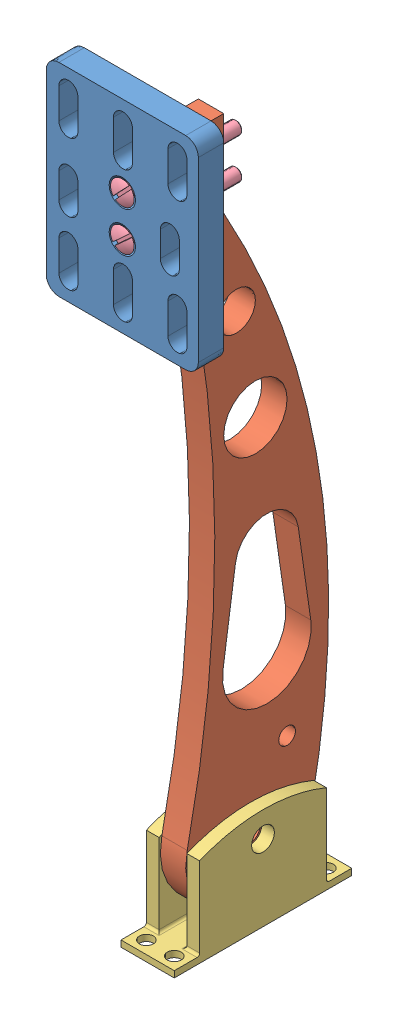
SolidWorks assembly Assem4, configuration Default. Lengths in mm.
Overall size (60 300 82.63).
5 component instances, 4 part files, 9 mates.
Components (placement in the parent):
- Accellerator Pedal-1: Accellerator Pedal [Default] at (-107.6215 -14.9156 18.9179) size (60 80 10)
- Pedal support-1: Pedal support [Default] at (-72.6377 -204.9156 -16.0821) x (-1 0 0) z (0 0 -1) size (10 275 71.45)
- Base Pedal Interface-1: Base Pedal Interface [Default] at (-88.3912 -234.9156 -41.0821) size (21 40 70)
- din_en_iso2010_m5x45_4_8-1: din_en_iso2010_m5x45_4_8 [Default] at (-77.6215 33.0844 30.1179) x (-0.68633 -0.72729 0) z (0 0 -1) size (9.22 9.3 46.18)
- din_en_iso2010_m5x45_4_8-2: din_en_iso2010_m5x45_4_8 [Default] at (-77.6215 17.0844 30.1179) x (-0.744447 -0.667681 0) z (0 0 -1) size (9.22 9.3 46.18)
Mates (geometry in assembly coordinates):
- Coincident1: coincident anti-aligned: circle of Accellerator Pedal-1; circle of Pedal support-1
- Coincident2: coincident anti-aligned: circle of Accellerator Pedal-1; circle of Pedal support-1
- Concentric1: concentric anti-aligned: circle of Pedal support-1; circle of Base Pedal Interface-1
- Distance1: distance = 0.5 mm anti-aligned: plane of Pedal support-1 through (-72.6377 -97.6766 -44.0529) normal (1 0 0); plane of Base Pedal Interface-1 through (-72.1377 -184.9156 8.9179) normal (-1 0 0)
- Concentric2: concentric aligned: cylinder of Pedal support-1 through (-77.6215 33.0844 18.9179) axis (0 0 1) radius 2.75; cylinder of din_en_iso2010_m5x45_4_8-1 through (-77.6215 33.0844 30.1179) axis (0 0 1) radius 2.5
- Concentric3: concentric aligned: circle of din_en_iso2010_m5x45_4_8-1; circle of Accellerator Pedal-1
- Distance2: distance = 10 mm aligned: plane of din_en_iso2010_m5x45_4_8-1 through (-77.6215 33.0844 -16.0821) normal (0 0 -1); plane of Pedal support-1 through (-82.6377 11.0641 -6.0821) normal (0 0 -1)
- Concentric4: concentric: cylinder of Pedal support-1 through (-77.6215 17.0844 18.9179) axis (0 0 1) radius 2.75; cylinder of din_en_iso2010_m5x45_4_8-2 through (-77.6215 17.0844 30.1179) axis (0 0 1) radius 2.5
- Distance3: distance = 10 mm aligned: plane of din_en_iso2010_m5x45_4_8-2 through (-77.6215 17.0844 -16.0821) normal (0 0 -1); plane of Pedal support-1 through (-82.6377 11.0641 -6.0821) normal (0 0 -1)
